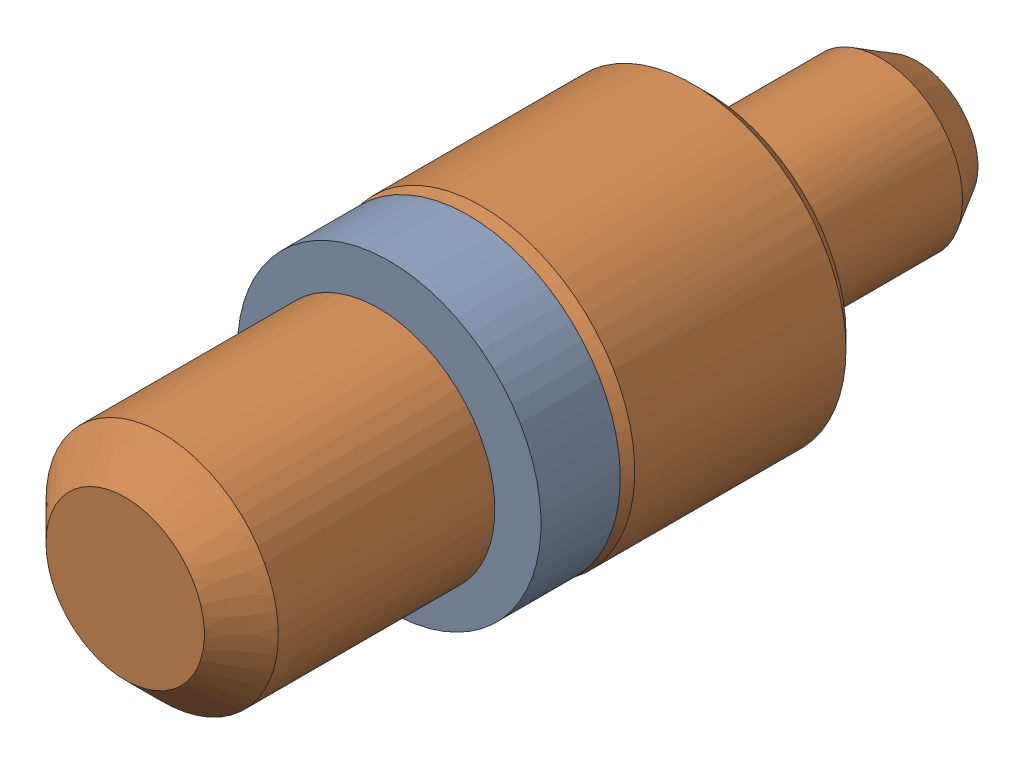
SolidWorks assembly Pogo Pin Asmbly_5, configuration Default. Lengths in mm.
Overall size (2.95 2.95 7.62).
2 component instances, 2 part files, 0 mates.
Components (placement in the parent):
- Pogo O-Ring-1: Pogo O-Ring [Default] at (75.1152 45.5101 -6.223) size (2.92 2.92 0.76)
- Pogo Contact Pin-1: Pogo Contact Pin [Default] at (75.1152 45.5101 -6.223) size (2.95 2.95 7.62)
